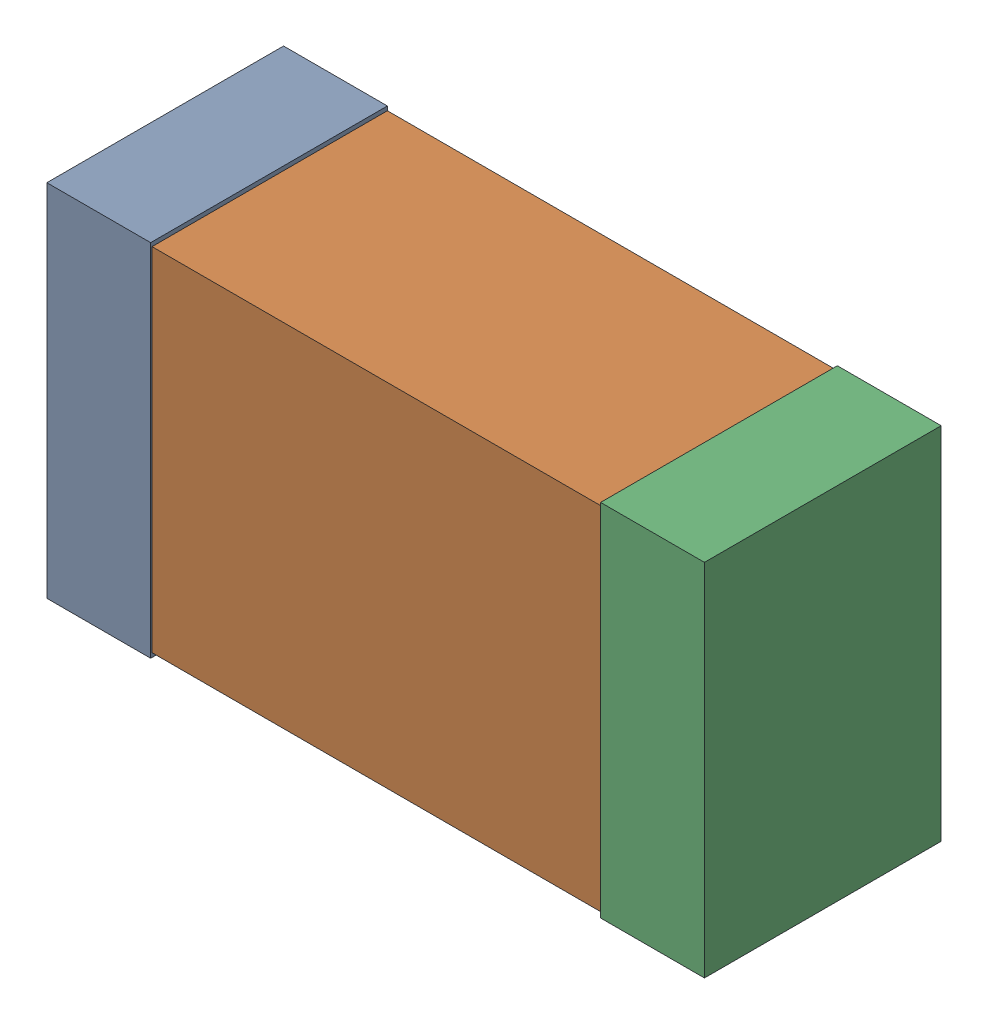
SolidWorks assembly C4Kanaloa_v2.0.0_GPIO_b, configuration Default. Lengths in mm.
Overall size (2.38 1.3 0.85).
6 component instances, 2 part files, 0 mates.
Components (placement in the parent):
- 352877648-1: 352877648 [Default] at (78.502 80.772 0) size (0.38 1.3 0.85)
  - Extruded_14-1: Extruded_14 [Default] at origin size (0.38 1.3 0.85)
- 352877392-1: 352877392 [Default] at (79.502 80.772 0) size (2.2 1.27 0.85)
  - Extruded_15-1: Extruded_15 [Default] at origin size (2.2 1.27 0.85)
- 352877648-2: 352877648 [Default] at (80.502 80.772 0) size (0.38 1.3 0.85)
  - Extruded_14-1: Extruded_14 [Default] at origin size (0.38 1.3 0.85)
